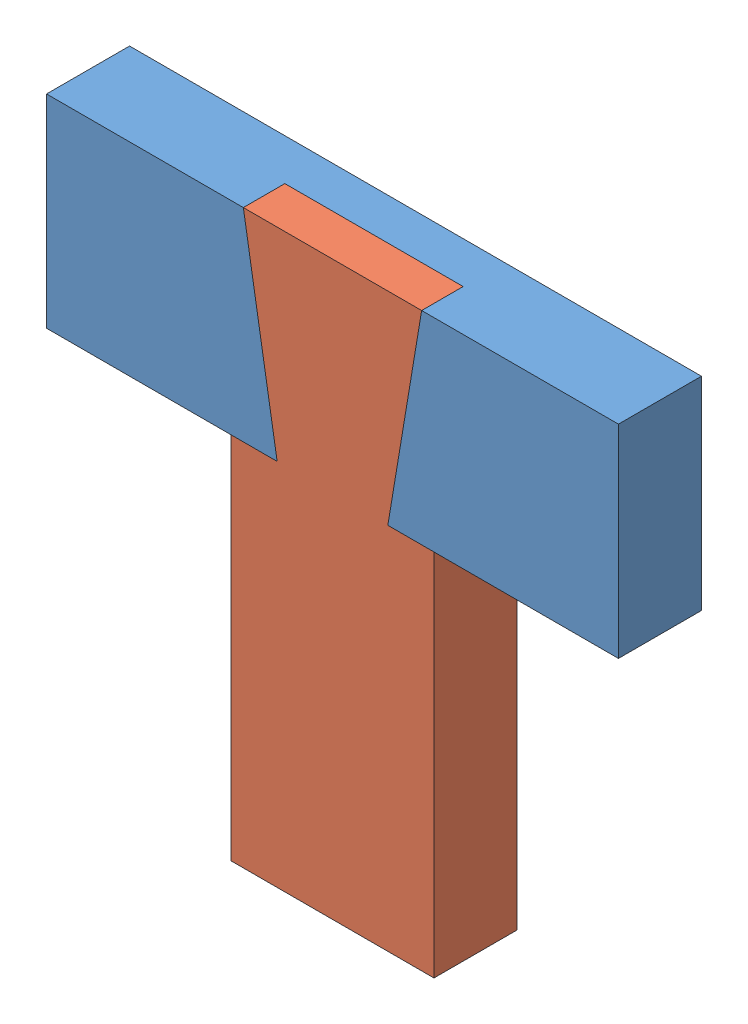
SolidWorks assembly DOVETAIL HALVING ASSM, configuration Default. Lengths in mm.
Overall size (124 124 18).
2 component instances, 2 part files, 3 mates.
Components (placement in the parent):
- TOP PIECE A-1: TOP PIECE A [Default] at (-65.3803 -10.3775 -16.1124) size (124 44 18)
- VERTICAL PIECE B-1: VERTICAL PIECE B [Default] at (-25.3803 33.6225 -16.1124) size (44 124 18)
Mates (geometry in assembly coordinates):
- Coincident1: coincident: plane of TOP PIECE A-1 through (-65.3803 33.6225 1.8876) normal (0 1 0); plane of VERTICAL PIECE B-1 through (-25.3803 33.6225 1.8876) normal (0 1 0)
- Coincident2: coincident: plane of TOP PIECE A-1 through (-15.3803 -10.3775 -7.1124) normal (0.986401 0.164359 0); plane of VERTICAL PIECE B-1 through (-15.3803 -10.3775 1.8876) normal (-0.986401 -0.164359 0)
- Coincident3: coincident aligned: plane of TOP PIECE A-1 through (-65.3803 33.6225 1.8876) normal (0 0 1); plane of VERTICAL PIECE B-1 through (-25.3803 -90.3775 1.8876) normal (0 0 1)
